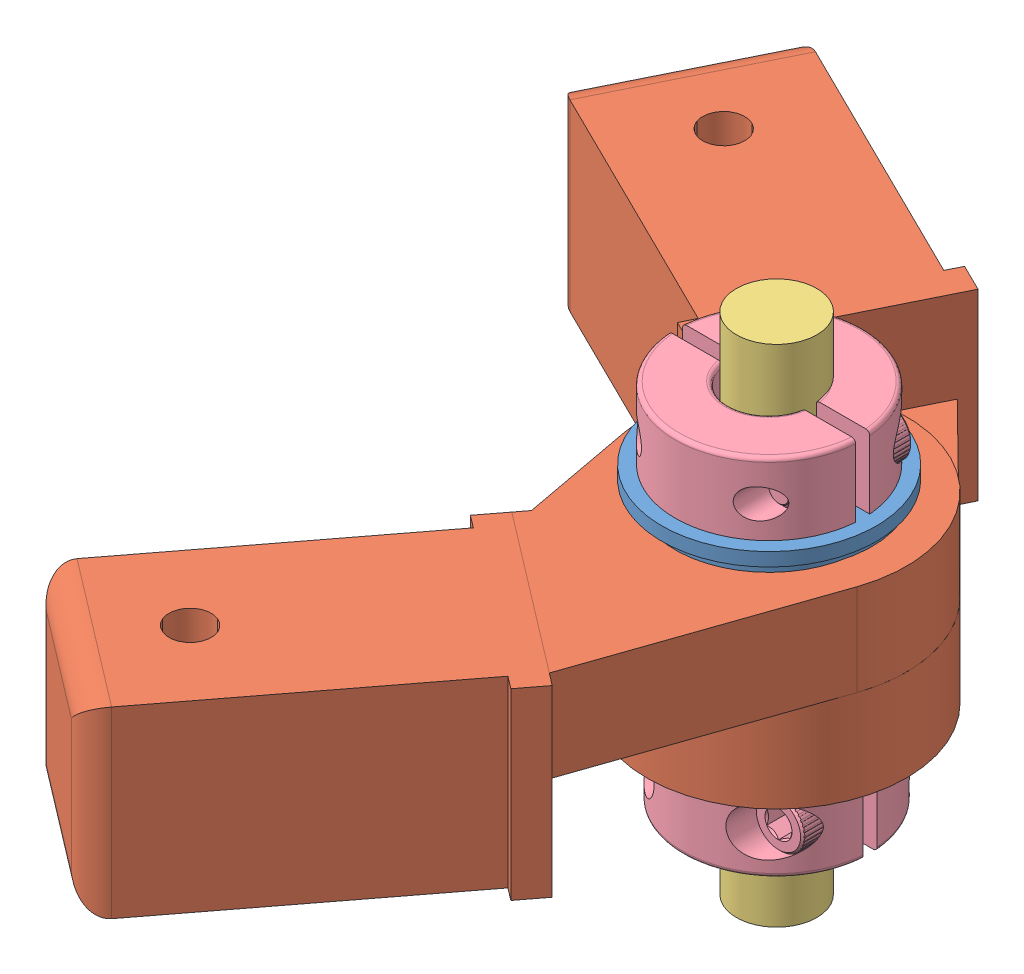
SolidWorks assembly AA Climb Insert v2, configuration Default. Lengths in mm.
Overall size (92.26 59.8 115.41).
7 component instances, 4 part files, 3 mates.
Components (placement in the parent):
- Ball Bearing-1: Ball Bearing [Default] at (-81.0287 -2.4491 -5.6602) x (1 0 0) z (0 1 0) size (25.4 25.4 10.32)
- Climber Insert 1-1: Climber Insert 1 [Default] at (-136.2666 -5.4773 -34.7042) x (0.442723 0 -0.896658) z (0.896658 0 0.442723) size (40.77 21.73 77.76)
- Ball Bearing-2: Ball Bearing [Default] at (-81.0287 15.3865 -4.7702) x (1 0 0) z (0 -1 0) size (25.4 25.4 10.32)
- Climber Insert 1-2: Climber Insert 1 [Default] at (-117.6033 16.7477 44.9074) x (0.795102 0 0.606476) z (0.606476 0 -0.795102) size (40.77 21.73 77.76)
- Rotary Shaft-1: Rotary Shaft [Default] at (-81.0287 -2.4491 -5.6602) x (1 0 0) z (0 -1 0) size (9.53 9.53 59.8)
- Clamping Two-Piece Shaft Collar-1: Clamping Two-Piece Shaft Collar [Default] at (-81.0287 -10.5629 -5.6602) x (1 0 0) z (0 -1 0) size (22.18 22.23 9.54)
- Clamping Two-Piece Shaft Collar-2: Clamping Two-Piece Shaft Collar [Default] at (-81.0287 23.5002 -4.7702) x (1 0 0) z (0 1 0) size (22.18 22.23 9.54)
Mates (geometry in assembly coordinates):
- Concentric1: concentric anti-aligned: circle of Ball Bearing-1; circle of Climber Insert 1-1
- Coincident1: coincident anti-aligned: plane of Ball Bearing-1 through (-81.0287 -5.2273 -15.6589) normal (0 1 0); plane of Climber Insert 1-1 through (-136.1559 -5.2273 -34.9284) normal (0 -1 0)
- Coincident4: coincident anti-aligned: circle of Climber Insert 1-1; circle of Climber Insert 1-2
